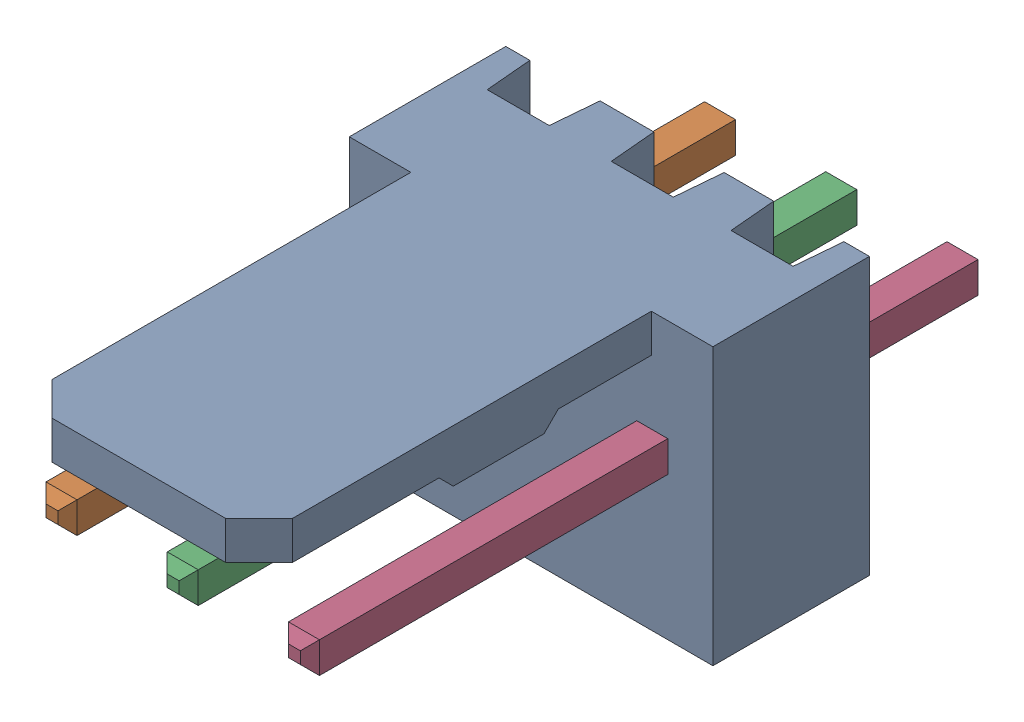
SolidWorks assembly Molex PCB 3 pin v2 v6_5, configuration Default. Lengths in mm.
Overall size (7.62 5.79 14.92).
4 component instances, 2 part files, 0 mates.
Components (placement in the parent):
- BASE9710016_2-1: BASE9710016_2 [Default] at (2.54 2.895 -8.22) size (7.62 5.79 11.5)
- PINO9710016_2-1: PINO9710016_2 [Default] at (1.27 3.325 -0.72) size (0.65 0.65 14.2)
- PINO9710016_2-2: PINO9710016_2 [Default] at (3.81 3.325 -0.72) size (0.65 0.65 14.2)
- PINO9710016_2-3: PINO9710016_2 [Default] at (6.35 3.325 -0.72) size (0.65 0.65 14.2)
